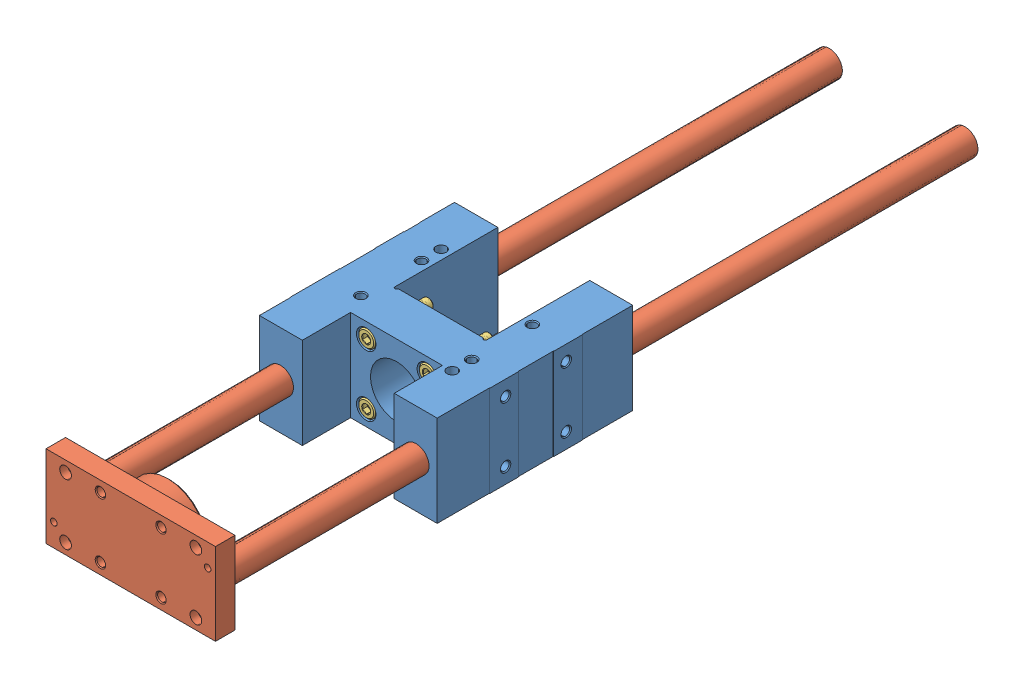
SolidWorks assembly 150292 FENG-50-400-KF---(asm_0), configuration Default. Lengths in mm.
Overall size (137 70 588).
6 component instances, 3 part files, 15 mates.
Components (placement in the parent):
- 150292 FENG-50-KF---(GK)-1: 150292 FENG-50-KF---(GK) [Default] at origin size (137 70 150)
- 150292 FENG-50-400-KF---(JS)-1: 150292 FENG-50-400-KF---(JS) [Default] at (0 0 148.9048) size (130 63 588)
- DIN-912 - M8x40(F)-1: DIN-912 - M8x40(F) [Default] at (23.25 23.25 26) x (1 0 0) z (0 -1 0) size (13 48.35 13)
- DIN-912 - M8x40(F)-2: DIN-912 - M8x40(F) [Default] at (-23.25 23.25 26) x (1 0 0) z (0 -1 0) size (13 48.35 13)
- DIN-912 - M8x40(F)-3: DIN-912 - M8x40(F) [Default] at (23.25 -23.25 26) x (1 0 0) z (0 -1 0) size (13 48.35 13)
- DIN-912 - M8x40(F)-4: DIN-912 - M8x40(F) [Default] at (-23.25 -23.25 26) x (1 0 0) z (0 -1 0) size (13 48.35 13)
Mates (geometry in assembly coordinates):
- Coincident1: coincident: line of 150292 FENG-50-KF---(GK)-1 through (0 0 80.9) axis (0 0 -1); line of 150292 FENG-50-400-KF---(JS)-1 through (0 0 229.8048) axis (0 0 -1)
- Angle3: planar angle = 0 rad: plane of 150292 FENG-50-400-KF---(JS)-1 through (0 0 148.9048) normal (1 0 0); plane of 150292 FENG-50-KF---(GK)-1 through (0 0 0) normal (1 0 0)
- Distance2: distance = 0 mm aligned: plane of 150292 FENG-50-KF---(GK)-1 through (0 0 26) normal (0 0 1); plane of DIN-912 - M8x40(F)-1 through (23.25 23.25 26) normal (0 0 1)
- Coincident2: coincident aligned: line of 150292 FENG-50-KF---(GK)-1 through (23.25 23.25 80.9) axis (0 0 -1); line of DIN-912 - M8x40(F)-1 through (23.25 23.25 76) axis (0 0 -1)
- Angle6: planar angle = 0 rad aligned: plane of DIN-912 - M8x40(F)-1 through (23.25 23.25 26) normal (1 0 0); plane of 150292 FENG-50-KF---(GK)-1 through (23.25 0 0) normal (1 0 0)
- Distance4: distance = 0 mm aligned: plane of 150292 FENG-50-KF---(GK)-1 through (0 0 26) normal (0 0 1); plane of DIN-912 - M8x40(F)-2 through (-23.25 23.25 26) normal (0 0 1)
- Coincident3: coincident aligned: line of 150292 FENG-50-KF---(GK)-1 through (-23.25 23.25 80.9) axis (0 0 -1); line of DIN-912 - M8x40(F)-2 through (-23.25 23.25 76) axis (0 0 -1)
- Angle9: planar angle = 0 rad aligned: plane of DIN-912 - M8x40(F)-2 through (-23.25 23.25 26) normal (1 0 0); plane of 150292 FENG-50-KF---(GK)-1 through (-23.25 0 0) normal (1 0 0)
- Distance6: distance = 0 mm aligned: plane of 150292 FENG-50-KF---(GK)-1 through (0 0 26) normal (0 0 1); plane of DIN-912 - M8x40(F)-3 through (23.25 -23.25 26) normal (0 0 1)
- Coincident4: coincident aligned: line of 150292 FENG-50-KF---(GK)-1 through (23.25 -23.25 80.9) axis (0 0 -1); line of DIN-912 - M8x40(F)-3 through (23.25 -23.25 76) axis (0 0 -1)
- Angle12: planar angle = 0 rad aligned: plane of DIN-912 - M8x40(F)-3 through (23.25 -23.25 26) normal (1 0 0); plane of 150292 FENG-50-KF---(GK)-1 through (23.25 0 0) normal (1 0 0)
- Distance8: distance = 0 mm aligned: plane of 150292 FENG-50-KF---(GK)-1 through (0 0 26) normal (0 0 1); plane of DIN-912 - M8x40(F)-4 through (-23.25 -23.25 26) normal (0 0 1)
- Coincident5: coincident aligned: line of 150292 FENG-50-KF---(GK)-1 through (-23.25 -23.25 80.9) axis (0 0 -1); line of DIN-912 - M8x40(F)-4 through (-23.25 -23.25 76) axis (0 0 -1)
- Angle15: planar angle = 0 rad aligned: plane of DIN-912 - M8x40(F)-4 through (-23.25 -23.25 26) normal (1 0 0); plane of 150292 FENG-50-KF---(GK)-1 through (-23.25 0 0) normal (1 0 0)
- LimitDistance1: limit distance = 151.9048 mm anti-aligned: plane of 150292 FENG-50-400-KF---(JS)-1 through (0 0 222.9048) normal (0 0 -1); plane of 150292 FENG-50-KF---(GK)-1 through (-68.5 35 71) normal (0 0 1)
